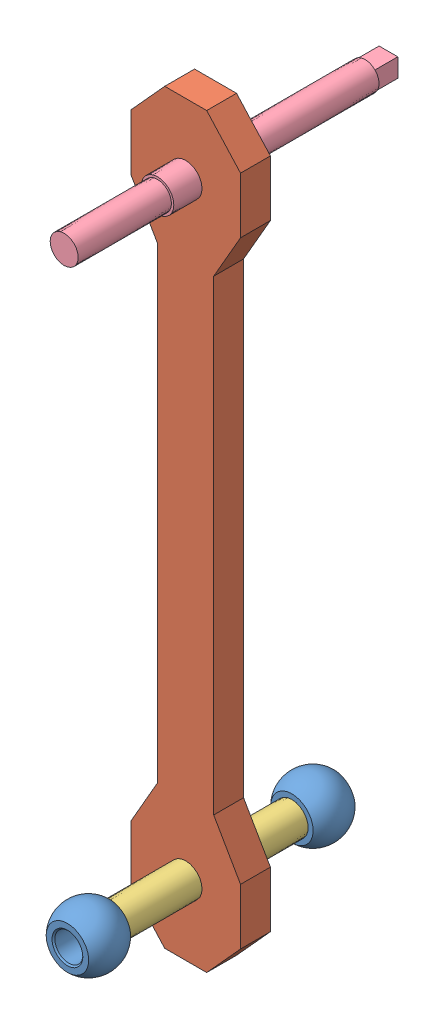
SolidWorks assembly BrazoCompleto, configuration Predeterminado. Lengths in mm.
Overall size (23.5 160 69.5).
5 component instances, 4 part files, 10 mates.
Components (placement in the parent):
- ball_Uniball-1: ball_Uniball [По умолчанию] at (-6 -5.0236 20.85) x (0.923728 -0.383049 0) z (0 0 1) size (12.8 12.8 9)
- ball_Uniball-2: ball_Uniball [По умолчанию] at (-6 -5.0236 -27.25) x (-1 0 0) z (0 0 -1) size (12.8 12.8 9)
- Brazo-1: Brazo [Predeterminado] at (-6 44.8272 0) x (-1 0 0) z (0 0 -1) size (23.5 160 6.4)
- Acople-Brazo-RUniball-1: Acople-Brazo-RUniball [Predeterminado] at (-6 -5.0236 20.85) x (-1 0 0) z (0 0 -1) size (19 19 48.1)
- Eje-Base-Brazo-1: Eje-Base-Brazo [Predeterminado] at (-6 124.9764 26.05) x (-1 0 0) z (0 0 -1) size (19 19 69.5)
Mates (geometry in assembly coordinates):
- Coincidente1: coincident anti-aligned: plane of Brazo-1 through (-6 44.8272 -6.4) normal (0 0 -1); plane of Eje-Base-Brazo-1 through (-6 124.9764 -6.4) normal (0 0 1)
- Concéntrica1: concentric aligned: circle of Brazo-1; circle of Eje-Base-Brazo-1
- Coincidente2: coincident anti-aligned: plane of Brazo-1 through (-6 44.8272 -6.4) normal (0 0 -1); plane of Acople-Brazo-RUniball-1 through (-6 -5.0236 -6.4) normal (0 0 1)
- Concéntrica2: concentric aligned: circle of Brazo-1; circle of Acople-Brazo-RUniball-1
- Coincidente3: coincident anti-aligned: plane of ball_Uniball-1 through (-8.8826 4.733 16.35) normal (0 0 -1); plane of Acople-Brazo-RUniball-1 through (-6 -5.0236 16.35) normal (0 0 1)
- Concéntrica3: concentric anti-aligned: circle of ball_Uniball-1; circle of Acople-Brazo-RUniball-1
- Coincidente4: coincident anti-aligned: plane of ball_Uniball-2 through (0.4 2.8847 -22.75) normal (0 0 1); plane of Acople-Brazo-RUniball-1 through (-6 -5.0236 -22.75) normal (0 0 -1)
- Concéntrica4: concentric aligned: circle of ball_Uniball-2; circle of Acople-Brazo-RUniball-1
- Coincidente5: coincident: line of Brazo-1 through (0 109.9764 0) axis (0 -1 0); plane of assembly
- Coincidente6: coincident aligned: plane of Brazo-1 through (-6 44.8272 0) normal (0 0 1); plane of assembly through (0 0 0) normal (0 0 1)
